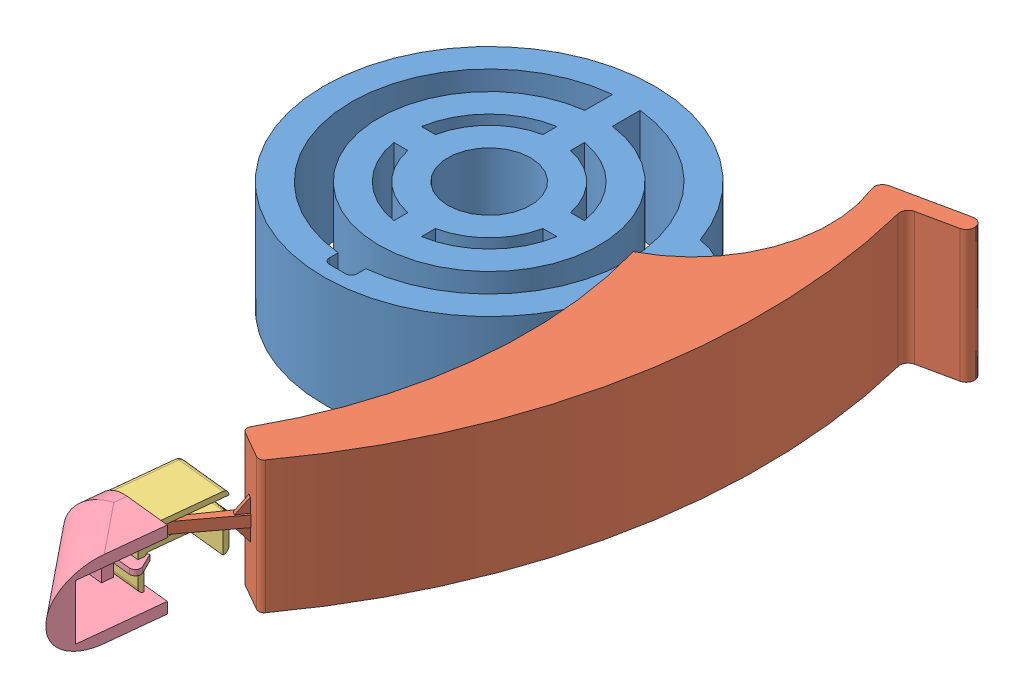
SolidWorks assembly test-peeler-assembly-packandgo, configuration Default. Lengths in mm.
Overall size (86.25 24 133.37).
5 component instances, 4 part files, 7 mates.
Components (placement in the parent):
- peeler-arm-holder-packandgo-1: peeler-arm-holder-packandgo [Default] at (-0.4616 12.3778 -6.6803) size (67.27 20 60)
- peeler-armSLDPRT-packandgo-1: peeler-armSLDPRT-packandgo [Default] at (-0.4494 10.3778 -5.781) x (0.999629 0 -0.027252) z (0.027252 0 0.999629) size (44.16 24 111.93)
- test-blade-packandgo-1: test-blade-packandgo [Default] at (4.0402 13.5549 73.6494) x (0.999844 0 0.017689) z (-0.017689 0 0.999844) size (16.7 14 34.06)
  - blade-holder-arm-packandgo-1: blade-holder-arm-packandgo [Default] at (0.5593 0.8229 -2.6525) x (0.996145 0 0.087727) z (-0.087727 0 0.996145) size (10 10 15)
  - blade-holder-packandgo-2: blade-holder-packandgo [Default] at (14.1842 5.8229 -3.4604) x (0.087727 0 -0.996145) z (0 1 0) size (20 15 14)
Mates (geometry in assembly coordinates):
- Concentric2: concentric aligned: cylinder of peeler-arm-holder-1 through (32.5384 12.3778 -6.6803) axis (0 1 0) radius 1; cylinder of peeler-armSLDPRT-packandgo-1 through (32.5384 30.3778 -6.6803) axis (0 1 0) radius 1
- Coincident2: coincident anti-aligned: plane of peeler-arm-holder-1 through (-0.4616 32.3778 -6.6803) normal (0 1 0); plane of peeler-armSLDPRT-packandgo-1 through (-52.9996 32.3778 15.6809) normal (0 -1 0)
- Coincident3: coincident anti-aligned: plane of peeler-armSLDPRT-1 through (-15.2418 10.3778 20.0308) normal (-0.497224 0 0.867622); plane of test-blade-1/blade-holder-clip-1 through (30.8108 27.3778 46.423) normal (0.497224 0 -0.867622)
- Coincident4: coincident anti-aligned: plane of peeler-armSLDPRT-1 through (26.4727 27.3778 43.9369) normal (0 -1 0); plane of test-blade-1/blade-holder-clip-1 through (22.2946 27.3778 62.2888) normal (0 1 0)
- Coincident5: coincident: line of peeler-armSLDPRT-1 through (19.0144 27.3778 56.9512) axis (0 -1 0); plane of test-blade-1/blade-holder-clip-1 through (26.4727 27.3778 43.9369) normal (-0.867622 0 -0.497224)
- Coincident6: coincident anti-aligned: plane of peeler-armSLDPRT-packandgo-1 through (-0.4494 23.3778 -5.781) normal (0 1 0); plane of test-blade-packandgo-1/blade-holder-arm-packandgo-1 through (4.6463 23.3778 71.0072) normal (0 -1 0)
- Concentric3: concentric aligned: cylinder of peeler-armSLDPRT-packandgo-1 through (12.3679 34.3778 69.3111) axis (0 -1 0) radius 0.5; cylinder of test-blade-packandgo-1/blade-holder-arm-packandgo-1 through (12.3679 21.8778 69.3111) axis (0 -1 0) radius 0.5
